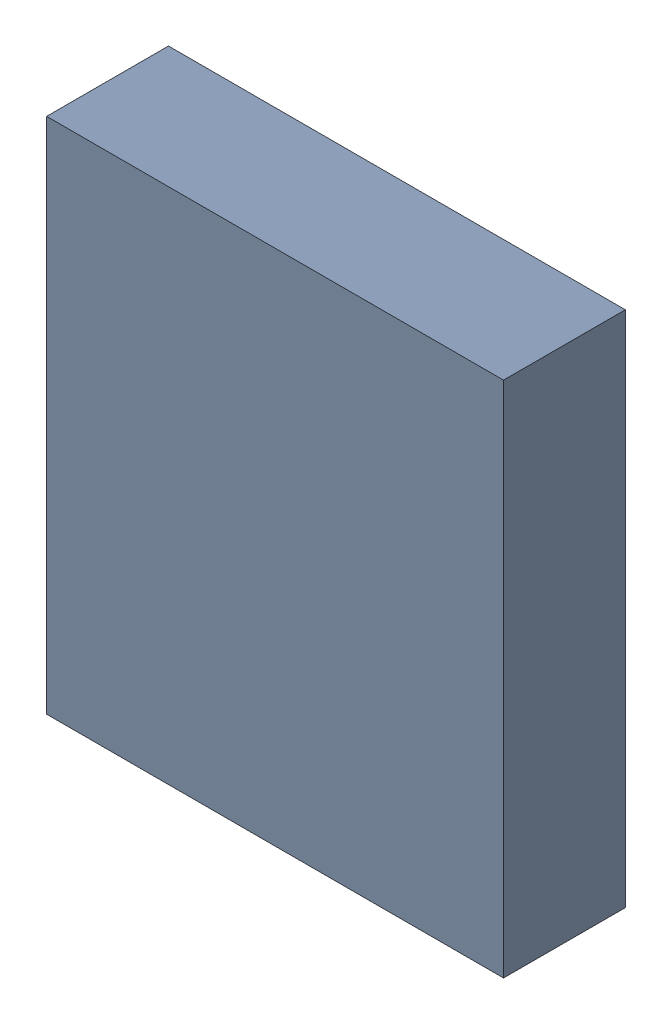
SolidWorks assembly U3, configuration Default. Lengths in mm.
Overall size (4.5 5.1 1.2).
2 component instances, 1 part files, 0 mates.
Components (placement in the parent):
- 1540840768-1: 1540840768 [Default] at (31.5 -27 -1.6115) size (4.5 5.1 1.2)
  - Extruded_4-1: Extruded_4 [Default] at origin size (4.5 5.1 1.2)
